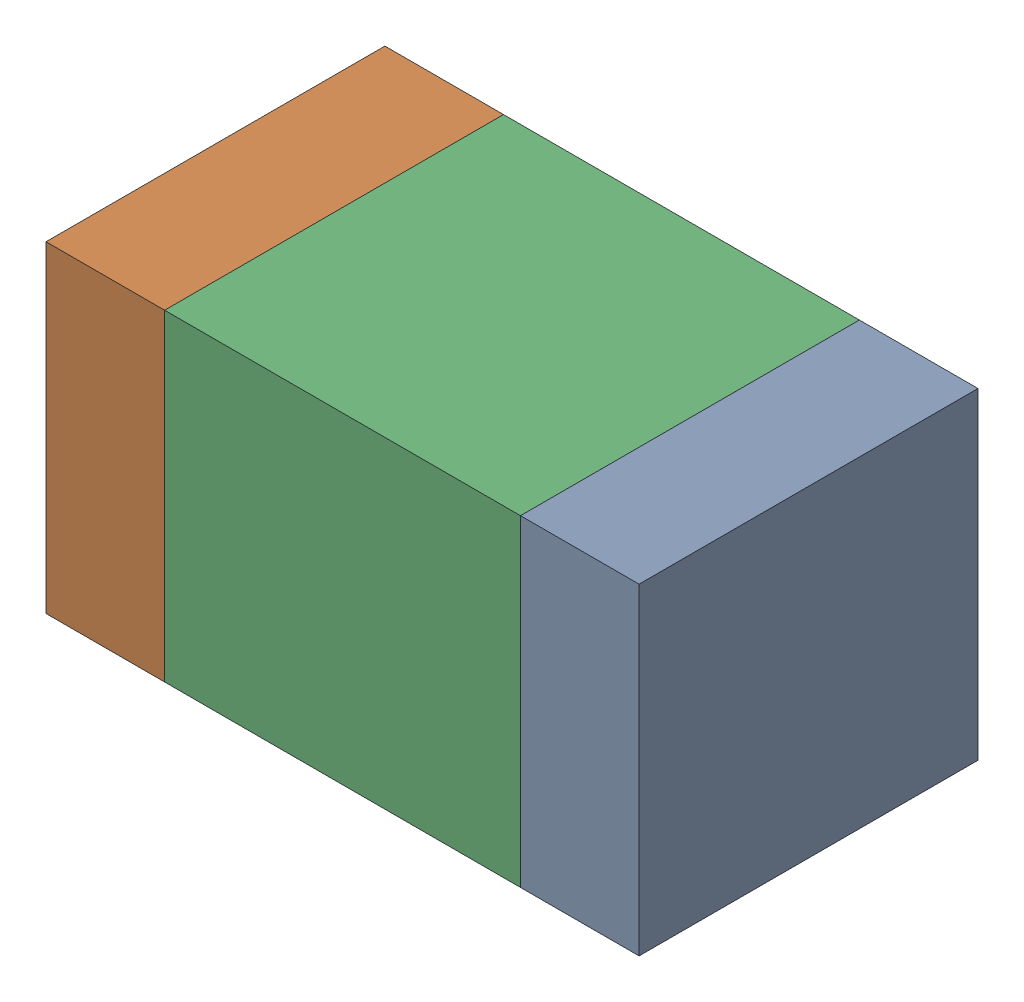
SolidWorks assembly C12, configuration Default. Lengths in mm.
Overall size (1.75 0.95 1).
6 component instances, 2 part files, 0 mates.
Components (placement in the parent):
- 959208936-1: 959208936 [Default] at (92.521 76.327 0) size (0.35 0.95 1)
  - Extruded-16-1: Extruded-16 [Default] at origin size (0.35 0.95 1)
- 959208936-2: 959208936 [Default] at (91.121 76.327 0) size (0.35 0.95 1)
  - Extruded-16-1: Extruded-16 [Default] at origin size (0.35 0.95 1)
- 959208800-1: 959208800 [Default] at (91.821 76.327 0) size (1.05 0.95 1)
  - Extruded-17-1: Extruded-17 [Default] at origin size (1.05 0.95 1)
